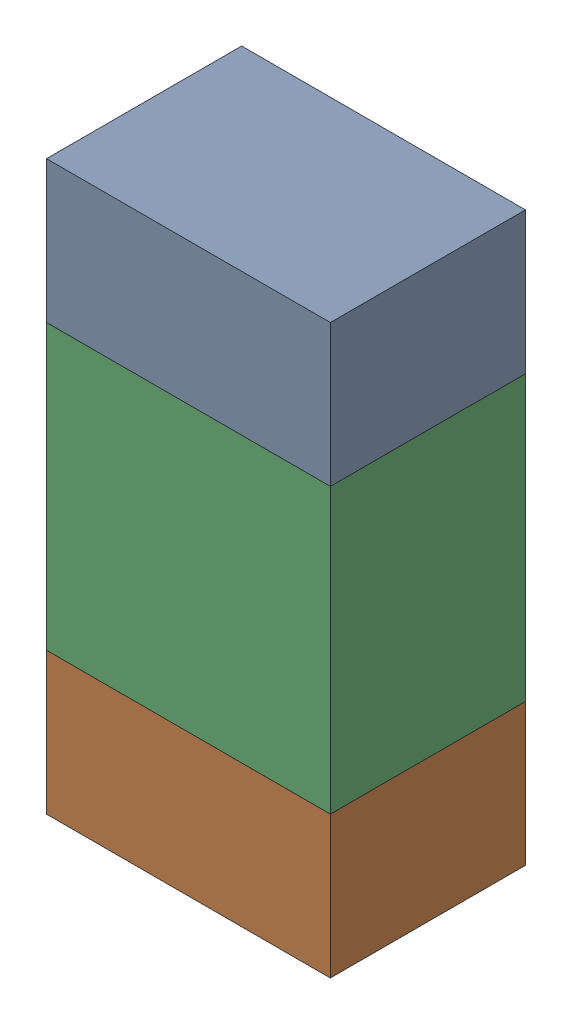
SolidWorks assembly R15, configuration ﾃﾞﾌｫﾙﾄ. Lengths in mm.
Overall size (0.8 1.6 0.55).
6 component instances, 2 part files, 0 mates.
Components (placement in the parent):
- 689261784-1: 689261784 [ﾃﾞﾌｫﾙﾄ] at (70.0001 53.8499 0) size (0.8 0.4 0.55)
  - Extruded_34-1: Extruded_34 [ﾃﾞﾌｫﾙﾄ] at origin size (0.8 0.4 0.55)
- 689261784-2: 689261784 [ﾃﾞﾌｫﾙﾄ] at (70.0001 52.6499 0) size (0.8 0.4 0.55)
  - Extruded_34-1: Extruded_34 [ﾃﾞﾌｫﾙﾄ] at origin size (0.8 0.4 0.55)
- 689261648-1: 689261648 [ﾃﾞﾌｫﾙﾄ] at (70.0001 53.25 0) size (0.8 0.8 0.55)
  - Extruded_33-1: Extruded_33 [ﾃﾞﾌｫﾙﾄ] at origin size (0.8 0.8 0.55)
